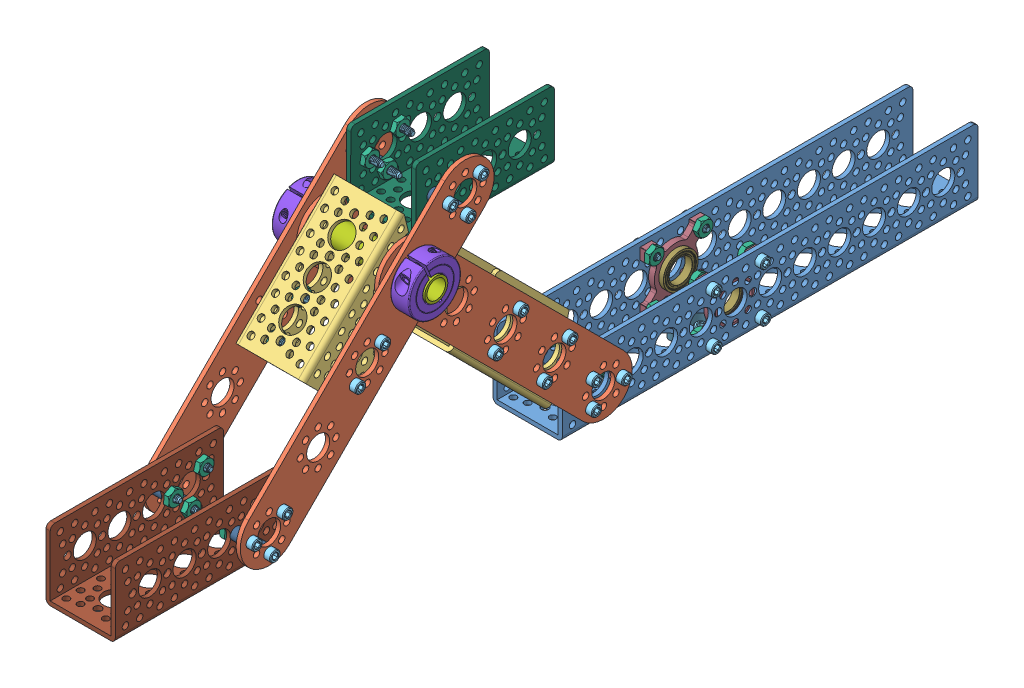
SolidWorks assembly Rocker-Bogie Assembly, configuration Default. Lengths in mm.
Overall size (76.23 183.41 474.44).
136 component instances, 15 part files, 93 mates.
Components (placement in the parent):
- 9 Aluminum Channel-1: 9 Aluminum Channel [Default] at (59.7969 112.1361 56.5133) size (38.1 38.1 228.6)
- Pattern F Bracket-1: Pattern F Bracket [Default] at (58.5269 185.0676 319.9448) x (0 0.707107 0.707107) z (0 -0.707107 0.707107) size (184.15 2.29 31.75)
- 3 Aluminum Channel Mod-1: 3 Aluminum Channel Mod [Default] at (59.7969 131.1861 293.004) x (1 0 0) z (0 0.707107 0.707107) size (38.1 38.1 76.2)
- 6-32 Washer-3: 6-32 Washer [Default] at (58.5269 124.2713 272.9781) x (0 0 -1) z (1 0 0) size (6.35 6.35 1.27)
- 6-32 Washer-6: 6-32 Washer [Default] at (58.5269 178.1528 326.8596) x (0 0 -1) z (1 0 0) size (6.35 6.35 1.27)
- 6-32 Washer-7: 6-32 Washer [Default] at (58.5269 191.9824 313.03) x (0 0 -1) z (1 0 0) size (6.35 6.35 1.27)
- 6-32 Washer-8: 6-32 Washer [Default] at (58.5269 165.0416 286.0892) x (0 -0.924225 -0.381849) z (1 0 0) size (6.35 6.35 1.27)
- 6-32 Washer-9: 6-32 Washer [Default] at (58.5269 151.212 299.9188) x (0 0 -1) z (1 0 0) size (6.35 6.35 1.27)
- 6-32_SHCS-2: 6-32_SHCS [6-32 SHCS X .375] at (65.7659 178.1528 326.8596) x (0 0.924225 0.381849) z (-1 0 0) size (5.74 5.74 13.03)
- 6-32_SHCS-6: 6-32_SHCS [6-32 SHCS X .375] at (65.7659 191.9824 313.03) x (0 0.924225 0.381849) z (-1 0 0) size (5.74 5.74 13.03)
- 6-32_SHCS-7: 6-32_SHCS [6-32 SHCS X .375] at (65.7659 165.0416 286.0892) x (0 0.924225 0.381849) z (-1 0 0) size (5.74 5.74 13.03)
- 6-32_SHCS-8: 6-32_SHCS [6-32 SHCS X .375] at (65.7659 124.2713 272.9781) x (0 0.924225 0.381849) z (-1 0 0) size (5.74 5.74 13.03)
- 6-32_SHCS-9: 6-32_SHCS [6-32 SHCS X .375] at (65.7659 151.212 299.9188) x (0 0 1) z (-1 0 0) size (5.74 5.74 13.03)
- hex_nut-1: hex_nut [#6-32] at (62.0829 191.9824 313.03) x (0 0.381849 -0.924225) z (0 -0.924225 -0.381849) size (7.92 2.9 10.06)
- hex_nut-2: hex_nut [#6-32] at (62.0829 151.212 299.9188) x (0 0.381849 -0.924225) z (0 -0.924225 -0.381849) size (7.92 2.9 10.06)
- hex_nut-3: hex_nut [#6-32] at (62.0829 124.2713 272.9781) x (0 0.381849 -0.924225) z (0 -0.924225 -0.381849) size (7.92 2.9 10.06)
- hex_nut-4: hex_nut [#6-32] at (62.0829 165.0416 286.0892) x (0 -0.870942 -0.491386) z (0 -0.491386 0.870942) size (7.92 2.9 10.06)
- hex_nut-5: hex_nut [#6-32] at (62.0829 178.1528 326.8596) x (0 0.381849 -0.924225) z (0 -0.924225 -0.381849) size (7.92 2.9 10.06)
- hex_nut-10: hex_nut [#6-32] at (62.0829 131.0154 256.2858) x (0 0.399577 0.9167) z (0 0.9167 -0.399577) size (7.92 2.9 10.06)
- hex_nut-11: hex_nut [#6-32] at (62.0829 138.338 272.7325) x (0 -0.936988 -0.349362) z (0 -0.349362 0.936988) size (7.92 2.9 10.06)
- 6-32 Washer-10: 6-32 Washer [Default] at (58.5269 131.0154 256.2858) x (0 0.71934 0.694658) z (1 0 0) size (6.35 6.35 1.27)
- 6-32 Washer-11: 6-32 Washer [Default] at (58.5269 138.338 272.7325) x (0 -0.999391 0.034899) z (1 0 0) size (6.35 6.35 1.27)
- 6-32_SHCS-10: 6-32_SHCS [6-32 SHCS X .375] at (65.7659 131.0154 256.2858) x (0 -0.9167 0.399577) z (-1 0 0) size (5.74 5.74 13.03)
- 6-32_SHCS-11: 6-32_SHCS [6-32 SHCS X .375] at (65.7659 138.338 272.7325) x (0 0.349362 -0.936988) z (-1 0 0) size (5.74 5.74 13.03)
- 3inch Aluminum Rod-1: 3inch Aluminum Rod [Default] at (41.0962 238.9491 373.8263) x (1 0 0) z (0 0.999969 -0.00781) size (76.2 12.7 12.7)
- .5in Collared Clamp-1: .5in Collared Clamp [6157K14] at (46.2556 238.9491 373.8263) x (0 -0.38629 0.922377) z (-1 0 0) size (28.57 28.59 10.38)
- 0.5 Nylon Plastic Washer-1: 0.5 Nylon Plastic Washer [Default] at (53.7009 238.9491 373.8263) x (0 0 -1) z (1 0 0) size (19.05 19.05 1.27)
- 0.5 Nylon Plastic Washer-2: 0.5 Nylon Plastic Washer [Default] at (59.7969 238.9491 373.8263) x (0 0 1) z (-1 0 0) size (19.05 19.05 1.27)
- 0.5 Nylon Plastic Washer-3: 0.5 Nylon Plastic Washer [Default] at (56.2409 238.9491 373.8263) x (0 0 1) z (-1 0 0) size (19.05 19.05 1.27)
- Pattern F Bracket-2: Pattern F Bracket [Default] at (51.4149 212.0374 400.7961) x (0 -0.706344 0.707869) z (0 0.707869 0.706344) size (184.15 2.29 31.75)
- 3 Aluminum Channel Mod-2: 3 Aluminum Channel Mod [Default] at (97.8969 265.8899 373.7973) x (-1 0 0) z (0 -0.706344 0.707869) size (38.1 38.1 76.2)
- 6-32_L0_25 Spacer-1: 6-32_L0_25 Spacer [Default] at (53.7009 205.1301 407.7184) size (6.35 6.35 6.35)
- 6-32_L0_25 Spacer-2: 6-32_L0_25 Spacer [Default] at (53.7009 256.0818 346.8671) size (6.35 6.35 6.35)
- 6-32_L0_25 Spacer-4: 6-32_L0_25 Spacer [Default] at (53.7009 148.435 454.7463) size (6.35 6.35 6.35)
- 6-32_L0_25 Spacer-5: 6-32_L0_25 Spacer [Default] at (53.7009 218.9448 393.8739) size (6.35 6.35 6.35)
- 6-32_SHCS-12: 6-32_SHCS [6-32 SHCS X .750] at (70.4649 205.1301 407.7184) x (0 0.924225 0.381849) z (-1 0 0) size (5.74 5.74 22.56)
- 6-32_SHCS-13: 6-32_SHCS [6-32 SHCS X .750] at (70.4649 256.0818 346.8671) x (0 0.924225 0.381849) z (-1 0 0) size (5.74 5.74 22.56)
- 6-32_SHCS-15: 6-32_SHCS [6-32 SHCS X .750] at (70.4649 218.9448 393.8739) x (0 0.924225 0.381849) z (-1 0 0) size (5.74 5.74 22.56)
- 6-32_SHCS-16: 6-32_SHCS [6-32 SHCS X .625] at (67.2899 148.435 454.7463) x (0 0.616938 0.787012) z (-1 0 0) size (5.74 5.74 19.38)
- 3.75 Aluminum Channel-1: 3.75 Aluminum Channel [Default] at (59.7969 139.1435 435.7063) x (1 0 0) z (0 0.001078 0.999999) size (38.1 38.1 95.25)
- hex_nut-12: hex_nut [#6-32] at (62.0829 256.0818 346.8671) x (0 0.381849 -0.924225) z (0 -0.924225 -0.381849) size (7.92 2.9 10.06)
- hex_nut-14: hex_nut [#6-32] at (62.0829 218.9448 393.8739) x (0 0.381849 -0.924225) z (0 -0.924225 -0.381849) size (7.92 2.9 10.06)
- hex_nut-15: hex_nut [#6-32] at (62.0829 205.1301 407.7184) x (0 0.381849 -0.924225) z (0 -0.924225 -0.381849) size (7.92 2.9 10.06)
- hex_nut-16: hex_nut [#6-32] at (62.0829 148.435 454.7463) x (0 -1 0) z (0 0 1) size (7.92 2.9 10.06)
- hex_nut-17: hex_nut [#6-32] at (62.0829 272.6463 339.8148) x (0 0.399577 0.9167) z (0 0.9167 -0.399577) size (7.92 2.9 10.06)
- hex_nut-18: hex_nut [#6-32] at (62.0829 266.2127 356.6292) x (0 -0.936988 -0.349362) z (0 -0.349362 0.936988) size (7.92 2.9 10.06)
- 6-32_L0_25 Spacer-6: 6-32_L0_25 Spacer [Default] at (53.7009 272.6463 339.8148) x (1 0 0) z (0 -0.71934 -0.694658) size (6.35 6.35 6.35)
- 6-32_L0_25 Spacer-7: 6-32_L0_25 Spacer [Default] at (53.7009 266.2127 356.6292) x (1 0 0) z (0 0.999391 -0.034899) size (6.35 6.35 6.35)
- 6-32_SHCS-17: 6-32_SHCS [6-32 SHCS X .750] at (70.4649 272.6463 339.8148) x (0 -0.9167 0.399577) z (-1 0 0) size (5.74 5.74 22.56)
- 6-32_SHCS-18: 6-32_SHCS [6-32 SHCS X .750] at (70.4649 266.2127 356.6292) x (0 0.349362 -0.936988) z (-1 0 0) size (5.74 5.74 22.56)
- hex_nut-19: hex_nut [#6-32] at (62.0829 164.9995 447.694) x (0 0.694658 -0.71934) z (0 -0.71934 -0.694658) size (7.92 2.9 10.06)
- hex_nut-20: hex_nut [#6-32] at (62.0829 158.5658 464.5084) x (0 0.034899 0.999391) z (0 0.999391 -0.034899) size (7.92 2.9 10.06)
- 6-32_L0_25 Spacer-8: 6-32_L0_25 Spacer [Default] at (53.7009 164.9995 447.694) x (1 0 0) z (0 -0.71934 -0.694658) size (6.35 6.35 6.35)
- 6-32_L0_25 Spacer-9: 6-32_L0_25 Spacer [Default] at (53.7009 158.5658 464.5084) x (1 0 0) z (0 0.999391 -0.034899) size (6.35 6.35 6.35)
- 6-32_SHCS-19: 6-32_SHCS [6-32 SHCS X .625] at (67.2899 164.9995 447.694) x (0 -0.99469 -0.102916) z (-1 0 0) size (5.74 5.74 19.38)
- 6-32_SHCS-20: 6-32_SHCS [6-32 SHCS X .625] at (67.2899 158.5658 464.5084) x (0 0.765001 -0.644029) z (-1 0 0) size (5.74 5.74 19.38)
- 6-32_L0_25 Spacer-10: 6-32_L0_25 Spacer [Default] at (103.9929 158.5658 464.5084) x (-1 0 0) z (0 -0.999391 0.034899) size (6.35 6.35 6.35)
- 6-32_SHCS-21: 6-32_SHCS [6-32 SHCS X .625] at (90.4039 158.5658 464.5084) x (0 -0.765001 0.644029) z (1 0 0) size (5.74 5.74 19.38)
- 6-32_SHCS-22: 6-32_SHCS [6-32 SHCS X .625] at (90.4039 148.435 454.7463) x (0 -0.616938 -0.787012) z (1 0 0) size (5.74 5.74 19.38)
- 6-32_L0_25 Spacer-11: 6-32_L0_25 Spacer [Default] at (103.9929 148.435 454.7463) x (-1 0 0) z (0 0 -1) size (6.35 6.35 6.35)
- 6-32_L0_25 Spacer-12: 6-32_L0_25 Spacer [Default] at (103.9929 164.9995 447.694) x (-1 0 0) z (0 0.71934 0.694658) size (6.35 6.35 6.35)
- 6-32_SHCS-23: 6-32_SHCS [6-32 SHCS X .625] at (90.4039 164.9995 447.694) x (0 0.99469 0.102916) z (1 0 0) size (5.74 5.74 19.38)
- Pattern F Bracket-3: Pattern F Bracket [Default] at (106.2789 212.0374 400.7961) x (0 0.706344 -0.707869) z (0 0.707869 0.706344) size (184.15 2.29 31.75)
- hex_nut-21: hex_nut [#6-32] at (95.6109 148.435 454.7463) x (0 -1 0) z (0 0 -1) size (7.92 2.9 10.06)
- hex_nut-22: hex_nut [#6-32] at (95.6109 158.5658 464.5084) x (0 0.034899 0.999391) z (0 -0.999391 0.034899) size (7.92 2.9 10.06)
- hex_nut-23: hex_nut [#6-32] at (95.6109 164.9995 447.694) x (0 0.694658 -0.71934) z (0 0.71934 0.694658) size (7.92 2.9 10.06)
- hex_nut-24: hex_nut [#6-32] at (95.6109 205.1301 407.7184) x (0 0.381849 -0.924225) z (0 0.924225 0.381849) size (7.92 2.9 10.06)
- 6-32_SHCS-24: 6-32_SHCS [6-32 SHCS X .750] at (87.2289 205.1301 407.7184) x (0 -0.924225 -0.381849) z (1 0 0) size (5.74 5.74 22.56)
- 6-32_SHCS-25: 6-32_SHCS [6-32 SHCS X .750] at (87.2289 218.9448 393.8739) x (0 -0.924225 -0.381849) z (1 0 0) size (5.74 5.74 22.56)
- hex_nut-25: hex_nut [#6-32] at (95.6109 218.9448 393.8739) x (0 0.381849 -0.924225) z (0 0.924225 0.381849) size (7.92 2.9 10.06)
- .5in Collared Clamp-2: .5in Collared Clamp [6157K14] at (111.4383 238.9491 373.8263) x (0 0.38629 -0.922377) z (1 0 0) size (28.57 28.59 10.38)
- 0.5 Nylon Plastic Washer-4: 0.5 Nylon Plastic Washer [Default] at (102.7229 238.9491 373.8263) x (0 0 -1) z (1 0 0) size (19.05 19.05 1.27)
- 0.5 Nylon Plastic Washer-5: 0.5 Nylon Plastic Washer [Default] at (102.7229 238.9491 373.8263) x (0 0 1) z (-1 0 0) size (19.05 19.05 1.27)
- 0.5 Nylon Plastic Washer-6: 0.5 Nylon Plastic Washer [Default] at (99.1669 238.9491 373.8263) x (0 0 1) z (-1 0 0) size (19.05 19.05 1.27)
- 6-32_L0_25 Spacer-13: 6-32_L0_25 Spacer [Default] at (103.9929 205.1301 407.7184) x (-1 0 0) z (0 0 -1) size (6.35 6.35 6.35)
- 6-32_L0_25 Spacer-14: 6-32_L0_25 Spacer [Default] at (103.9929 218.9448 393.8739) x (-1 0 0) z (0 0 -1) size (6.35 6.35 6.35)
- 6-32_L0_25 Spacer-15: 6-32_L0_25 Spacer [Default] at (103.9929 266.2127 356.6292) x (-1 0 0) z (0 -0.999391 0.034899) size (6.35 6.35 6.35)
- 6-32_L0_25 Spacer-16: 6-32_L0_25 Spacer [Default] at (103.9929 272.6463 339.8148) x (-1 0 0) z (0 0.71934 0.694658) size (6.35 6.35 6.35)
- 6-32_L0_25 Spacer-17: 6-32_L0_25 Spacer [Default] at (103.9929 256.0818 346.8671) x (-1 0 0) z (0 0 -1) size (6.35 6.35 6.35)
- 6-32_SHCS-26: 6-32_SHCS [6-32 SHCS X .750] at (87.2289 256.0818 346.8671) x (0 -0.924225 -0.381849) z (1 0 0) size (5.74 5.74 22.56)
- 6-32_SHCS-27: 6-32_SHCS [6-32 SHCS X .750] at (87.2289 266.2127 356.6292) x (0 -0.349362 0.936988) z (1 0 0) size (5.74 5.74 22.56)
- 6-32_SHCS-28: 6-32_SHCS [6-32 SHCS X .750] at (87.2289 272.6463 339.8148) x (0 0.9167 -0.399577) z (1 0 0) size (5.74 5.74 22.56)
- 6-32_SHCS-29: 6-32_SHCS [6-32 SHCS X .375] at (91.9279 191.9824 313.03) x (0 -0.924225 -0.381849) z (1 0 0) size (5.74 5.74 13.03)
- 6-32_SHCS-30: 6-32_SHCS [6-32 SHCS X .375] at (91.9279 165.0416 286.0892) x (0 -0.924225 -0.381849) z (1 0 0) size (5.74 5.74 13.03)
- 6-32_SHCS-31: 6-32_SHCS [6-32 SHCS X .375] at (91.9279 131.0154 256.2858) x (0 0.9167 -0.399577) z (1 0 0) size (5.74 5.74 13.03)
- 6-32_SHCS-32: 6-32_SHCS [6-32 SHCS X .375] at (91.9279 138.338 272.7325) x (0 -0.349362 0.936988) z (1 0 0) size (5.74 5.74 13.03)
- 6-32_SHCS-33: 6-32_SHCS [6-32 SHCS X .375] at (91.9279 151.212 299.9188) x (0 0 -1) z (1 0 0) size (5.74 5.74 13.03)
- 6-32_SHCS-34: 6-32_SHCS [6-32 SHCS X .375] at (91.9279 178.1528 326.8596) x (0 -0.924225 -0.381849) z (1 0 0) size (5.74 5.74 13.03)
- 6-32_SHCS-35: 6-32_SHCS [6-32 SHCS X .375] at (91.9279 124.2713 272.9781) x (0 -0.924225 -0.381849) z (1 0 0) size (5.74 5.74 13.03)
- 6-32 Washer-12: 6-32 Washer [Default] at (97.8969 131.0154 256.2858) x (0 0.71934 0.694658) z (1 0 0) size (6.35 6.35 1.27)
- 6-32 Washer-13: 6-32 Washer [Default] at (97.8969 124.2713 272.9781) x (0 0 -1) z (1 0 0) size (6.35 6.35 1.27)
- 6-32 Washer-14: 6-32 Washer [Default] at (97.8969 138.338 272.7325) x (0 -0.999391 0.034899) z (1 0 0) size (6.35 6.35 1.27)
- 6-32 Washer-15: 6-32 Washer [Default] at (97.8969 151.212 299.9188) x (0 0 -1) z (1 0 0) size (6.35 6.35 1.27)
- 6-32 Washer-16: 6-32 Washer [Default] at (97.8969 165.0416 286.0892) x (0 -0.924225 -0.381849) z (1 0 0) size (6.35 6.35 1.27)
- 6-32 Washer-17: 6-32 Washer [Default] at (97.8969 191.9824 313.03) x (0 0 -1) z (1 0 0) size (6.35 6.35 1.27)
- 6-32 Washer-18: 6-32 Washer [Default] at (97.8969 178.1528 326.8596) x (0 0 -1) z (1 0 0) size (6.35 6.35 1.27)
- Pattern F Bracket-4: Pattern F Bracket [Default] at (101.4529 185.0676 319.9448) x (0 -0.707107 -0.707107) z (0 0.707107 -0.707107) size (184.15 2.29 31.75)
- 0.5 Pillow Bearing Block-1: 0.5 Pillow Bearing Block [Default] at (54.9779 139.4622 174.7264) x (0 -0.904025 -0.427479) z (0 -0.427479 0.904025) size (44.3 7.64 44.3)
  - 0.5 Bearing-1: 0.5 Bearing [Default] at (1.0111 10.8528 17.222) size (19.05 3.97 19.05)
  - 0.5 Bearing Block-1: 0.5 Bearing Block [Default] at (1.0111 10.28 17.222) x (-0.904025 0 -0.427479) z (-0.427479 0 0.904025) size (33.27 5.08 33.27)
- 0.5 Pillow Bearing Block-2: 0.5 Pillow Bearing Block [Default] at (102.716 116.0492 198.1394) x (0 -0.427479 -0.904025) z (0 0.904025 -0.427479) size (44.3 7.64 44.3)
  - 0.5 Bearing-1: 0.5 Bearing [Default] at (1.0111 10.8528 17.222) size (19.05 3.97 19.05)
  - 0.5 Bearing Block-1: 0.5 Bearing Block [Default] at (1.0111 10.28 17.222) x (-0.904025 0 -0.427479) z (-0.427479 0 0.904025) size (33.27 5.08 33.27)
- 6-32_SHCS-36: 6-32_SHCS [6-32 SHCS X .375] at (69.3219 144.6564 176.3929) x (0 0.00007 1) z (-1 0 0) size (5.74 5.74 13.03)
- hex_nut-26: hex_nut [#6-32] at (65.2579 144.6564 176.3929) x (0 0.442098 -0.896967) z (0 -0.896967 -0.442098) size (7.92 2.9 10.06)
- 6-32_SHCS-37: 6-32_SHCS [6-32 SHCS X .375] at (69.3219 117.7157 176.3929) x (0 1 -0.00007) z (-1 0 0) size (5.74 5.74 13.03)
- 6-32_SHCS-38: 6-32_SHCS [6-32 SHCS X .375] at (69.3219 117.7157 203.3337) x (0 -0.00007 -1) z (-1 0 0) size (5.74 5.74 13.03)
- 6-32_SHCS-39: 6-32_SHCS [6-32 SHCS X .375] at (69.3219 144.6564 203.3337) x (0 -1 0.00007) z (-1 0 0) size (5.74 5.74 13.03)
- hex_nut-27: hex_nut [#6-32] at (65.2579 117.7157 176.3929) x (0 -0.896967 -0.442098) z (0 -0.442098 0.896967) size (7.92 2.9 10.06)
- hex_nut-28: hex_nut [#6-32] at (65.2579 117.7157 203.3337) x (0 -0.442098 0.896967) z (0 0.896967 0.442098) size (7.92 2.9 10.06)
- hex_nut-29: hex_nut [#6-32] at (65.2579 144.6564 203.3337) x (0 0.896967 0.442098) z (0 0.442098 -0.896967) size (7.92 2.9 10.06)
- 6-32_SHCS-40: 6-32_SHCS [6-32 SHCS X .375] at (88.3719 144.6564 176.3929) x (0 -0.00007 -1) z (1 0 0) size (5.74 5.74 13.03)
- hex_nut-30: hex_nut [#6-32] at (92.4359 144.6564 176.3929) x (0 0.442098 -0.896967) z (0 0.896967 0.442098) size (7.92 2.9 10.06)
- 6-32_SHCS-41: 6-32_SHCS [6-32 SHCS X .375] at (88.3719 117.7157 176.3929) x (0 -1 0.00007) z (1 0 0) size (5.74 5.74 13.03)
- 6-32_SHCS-42: 6-32_SHCS [6-32 SHCS X .375] at (88.3719 117.7157 203.3337) x (0 0.00007 1) z (1 0 0) size (5.74 5.74 13.03)
- 6-32_SHCS-43: 6-32_SHCS [6-32 SHCS X .375] at (88.3719 144.6564 203.3337) x (0 1 -0.00007) z (1 0 0) size (5.74 5.74 13.03)
- hex_nut-31: hex_nut [#6-32] at (92.4359 117.7157 176.3929) x (0 -0.896967 -0.442098) z (0 0.442098 -0.896967) size (7.92 2.9 10.06)
- hex_nut-32: hex_nut [#6-32] at (92.4359 117.7157 203.3337) x (0 -0.442098 0.896967) z (0 -0.896967 -0.442098) size (7.92 2.9 10.06)
- hex_nut-33: hex_nut [#6-32] at (92.4359 144.6564 203.3337) x (0 0.896967 0.442098) z (0 -0.442098 0.896967) size (7.92 2.9 10.06)
- 0.5 Bore Side Tapped Clamping Hub-1: 0.5 Bore Side Tapped Clamping Hub [Default] at (112.3725 93.4655 176.8061) size (20.57 7.21 26.29)
  - 545600-1: 545600 [Default] at (-33.5255 9.1455 13.0572) size (20.57 7.21 26.29)
- 6-32_SHCS-44: 6-32_SHCS [6-32 SHCS X .375] at (71.9322 104.8971 196.7781) x (1 0 0) z (0 1 0) size (5.74 5.74 13.03)
- 6-32_SHCS-45: 6-32_SHCS [6-32 SHCS X .375] at (71.9322 104.8971 182.9485) x (0 0 1) z (0 1 0) size (5.74 5.74 13.03)
- 6-32_SHCS-46: 6-32_SHCS [6-32 SHCS X .375] at (85.7617 104.8971 182.9485) x (-1 0 0) z (0 1 0) size (5.74 5.74 13.03)
- 6-32_SHCS-47: 6-32_SHCS [6-32 SHCS X .375] at (85.7617 104.8971 196.7781) x (0 0 -1) z (0 1 0) size (5.74 5.74 13.03)
- hex_nut-34: hex_nut [#6-32] at (95.6109 165.0416 286.0892) x (0 -0.870942 -0.491386) z (0 0.491386 -0.870942) size (7.92 2.9 10.06)
- hex_nut-35: hex_nut [#6-32] at (95.6109 151.212 299.9188) x (0 0.381849 -0.924225) z (0 0.924225 0.381849) size (7.92 2.9 10.06)
- hex_nut-36: hex_nut [#6-32] at (95.6109 138.338 272.7325) x (0 -0.936988 -0.349362) z (0 0.349362 -0.936988) size (7.92 2.9 10.06)
- hex_nut-37: hex_nut [#6-32] at (95.6109 124.2713 272.9781) x (0 0.381849 -0.924225) z (0 0.924225 0.381849) size (7.92 2.9 10.06)
- hex_nut-38: hex_nut [#6-32] at (95.6109 131.0154 256.2858) x (0 0.399577 0.9167) z (0 -0.9167 0.399577) size (7.92 2.9 10.06)
- hex_nut-39: hex_nut [#6-32] at (95.6109 191.9824 313.03) x (0 0.381849 -0.924225) z (0 0.924225 0.381849) size (7.92 2.9 10.06)
- hex_nut-40: hex_nut [#6-32] at (95.6109 178.1528 326.8596) x (0 0.381849 -0.924225) z (0 0.924225 0.381849) size (7.92 2.9 10.06)
- hex_nut-41: hex_nut [#6-32] at (95.6109 266.2127 356.6292) x (0 -0.936988 -0.349362) z (0 0.349362 -0.936988) size (7.92 2.9 10.06)
- hex_nut-42: hex_nut [#6-32] at (95.6109 272.6463 339.8148) x (0 0.399577 0.9167) z (0 -0.9167 0.399577) size (7.92 2.9 10.06)
- hex_nut-43: hex_nut [#6-32] at (95.6109 256.0818 346.8671) x (0 0.381849 -0.924225) z (0 0.924225 0.381849) size (7.92 2.9 10.06)
- 3 Aluminum Channel-2: 3 Aluminum Channel [Default] at (60.0509 246.7492 289.7271) x (1 0 0) z (0 0.001078 0.999999) size (38.1 38.1 76.2)
Mates (geometry in assembly coordinates):
- Concentric1: concentric aligned: cylinder of 9 Aluminum Channel-1 through (97.8969 124.2713 272.9781) axis (1 0 0) radius 1.778; cylinder of 6-32_SHCS-8 through (43.5409 124.2713 272.9781) axis (1 0 0) radius 2.8702
- Concentric2: concentric anti-aligned: cylinder of 9 Aluminum Channel-1 through (97.8969 124.2713 272.9781) axis (1 0 0) radius 1.778; cylinder of 6-32 Washer-3 through (59.7969 124.2713 272.9781) axis (-1 0 0) radius 3.175
- Concentric3: concentric aligned: cylinder of 9 Aluminum Channel-1 through (97.8969 124.2713 272.9781) axis (1 0 0) radius 1.778; cylinder of hex_nut-3 through (62.159 124.2713 272.9781) axis (1 0 0) radius 1.323
- Concentric4: concentric aligned: cylinder of 3 Aluminum Channel Mod-1 through (97.8969 151.212 299.9188) axis (1 0 0) radius 1.778; cylinder of 6-32_SHCS-9 through (43.5409 151.212 299.9188) axis (1 0 0) radius 2.8702
- Concentric5: concentric anti-aligned: cylinder of 3 Aluminum Channel Mod-1 through (97.8969 151.212 299.9188) axis (1 0 0) radius 1.778; cylinder of 6-32 Washer-9 through (59.7969 151.212 299.9188) axis (-1 0 0) radius 3.175
- Concentric6: concentric aligned: cylinder of 3 Aluminum Channel Mod-1 through (97.8969 151.212 299.9188) axis (1 0 0) radius 1.778; cylinder of hex_nut-2 through (62.159 151.212 299.9188) axis (1 0 0) radius 1.323
- Concentric7: concentric aligned: cylinder of 3 Aluminum Channel Mod-1 through (97.8969 165.0416 286.0892) axis (1 0 0) radius 1.778; cylinder of 6-32_SHCS-7 through (43.5409 165.0416 286.0892) axis (1 0 0) radius 2.8702
- Concentric8: concentric anti-aligned: circle of hex_nut-4; cylinder of 6-32 Washer-8 through (59.7969 165.0416 286.0892) axis (-1 0 0) radius 3.175
- Concentric9: concentric aligned: circle of hex_nut-4; cylinder of 3 Aluminum Channel Mod-1 through (97.8969 165.0416 286.0892) axis (1 0 0) radius 1.778
- Concentric10: concentric anti-aligned: cylinder of 3 Aluminum Channel Mod-1 through (97.8969 191.9824 313.03) axis (1 0 0) radius 1.778; cylinder of 6-32 Washer-7 through (59.7969 191.9824 313.03) axis (-1 0 0) radius 3.175
- Concentric11: concentric aligned: cylinder of 3 Aluminum Channel Mod-1 through (97.8969 191.9824 313.03) axis (1 0 0) radius 1.778; cylinder of 6-32_SHCS-6 through (43.5409 191.9824 313.03) axis (1 0 0) radius 2.8702
- Concentric12: concentric aligned: cylinder of 3 Aluminum Channel Mod-1 through (97.8969 191.9824 313.03) axis (1 0 0) radius 1.778; cylinder of hex_nut-1 through (62.159 191.9824 313.03) axis (1 0 0) radius 1.323
- Concentric13: concentric anti-aligned: cylinder of 3 Aluminum Channel Mod-1 through (97.8969 178.1528 326.8596) axis (1 0 0) radius 1.778; cylinder of 6-32 Washer-6 through (59.7969 178.1528 326.8596) axis (-1 0 0) radius 3.175
- Concentric14: concentric aligned: cylinder of 3 Aluminum Channel Mod-1 through (97.8969 178.1528 326.8596) axis (1 0 0) radius 1.778; cylinder of 6-32_SHCS-2 through (43.5409 178.1528 326.8596) axis (1 0 0) radius 2.8702
- Concentric15: concentric aligned: cylinder of 3 Aluminum Channel Mod-1 through (97.8969 178.1528 326.8596) axis (1 0 0) radius 1.778; cylinder of hex_nut-5 through (62.159 178.1528 326.8596) axis (1 0 0) radius 1.323
- Coincident1: coincident aligned: plane of 9 Aluminum Channel-1 through (59.7969 112.1361 285.1133) normal (-1 0 0); plane of 3 Aluminum Channel Mod-1 through (59.7969 185.0676 346.8856) normal (-1 0 0)
- Coincident2: coincident anti-aligned: plane of 9 Aluminum Channel-1 through (59.7969 112.1361 285.1133) normal (-1 0 0); plane of 6-32 Washer-3 through (59.7969 124.2713 272.9781) normal (1 0 0)
- Coincident3: coincident anti-aligned: plane of 9 Aluminum Channel-1 through (59.7969 112.1361 285.1133) normal (-1 0 0); plane of 6-32 Washer-9 through (59.7969 151.212 299.9188) normal (1 0 0)
- Coincident5: coincident anti-aligned: plane of 9 Aluminum Channel-1 through (59.7969 112.1361 285.1133) normal (-1 0 0); plane of 6-32 Washer-7 through (59.7969 191.9824 313.03) normal (1 0 0)
- Coincident6: coincident anti-aligned: plane of 9 Aluminum Channel-1 through (59.7969 112.1361 285.1133) normal (-1 0 0); plane of 6-32 Washer-6 through (59.7969 178.1528 326.8596) normal (1 0 0)
- Coincident7: coincident anti-aligned: plane of 9 Aluminum Channel-1 through (59.7969 112.1361 285.1133) normal (-1 0 0); plane of 6-32 Washer-8 through (59.7969 165.0416 286.0892) normal (1 0 0)
- Coincident8: coincident anti-aligned: plane of Pattern F Bracket-1 through (58.5269 131.1861 266.0633) normal (1 0 0); plane of 6-32 Washer-3 through (58.5269 124.2713 272.9781) normal (-1 0 0)
- Concentric16: concentric anti-aligned: cylinder of 9 Aluminum Channel-1 through (97.8969 131.1861 266.0633) axis (1 0 0) radius 6.3627; cylinder of Pattern F Bracket-1 through (56.2409 131.1861 266.0633) axis (-1 0 0) radius 6.3627
- Concentric17: concentric anti-aligned: cylinder of 9 Aluminum Channel-1 through (97.8969 124.2713 272.9781) axis (1 0 0) radius 1.778; cylinder of Pattern F Bracket-1 through (56.2409 124.2713 272.9781) axis (-1 0 0) radius 1.778
- Coincident9: coincident anti-aligned: plane of Pattern F Bracket-1 through (56.2409 131.1861 266.0633) normal (-1 0 0); plane of 6-32_SHCS-8 through (56.2409 124.2713 272.9781) normal (1 0 0)
- Coincident10: coincident anti-aligned: plane of Pattern F Bracket-1 through (56.2409 131.1861 266.0633) normal (-1 0 0); plane of 6-32_SHCS-7 through (56.2409 165.0416 286.0892) normal (1 0 0)
- Coincident11: coincident anti-aligned: plane of Pattern F Bracket-1 through (56.2409 131.1861 266.0633) normal (-1 0 0); plane of 6-32_SHCS-9 through (56.2409 151.212 299.9188) normal (1 0 0)
- Coincident12: coincident anti-aligned: plane of Pattern F Bracket-1 through (56.2409 131.1861 266.0633) normal (-1 0 0); plane of 6-32_SHCS-6 through (56.2409 191.9824 313.03) normal (1 0 0)
- Coincident13: coincident anti-aligned: plane of Pattern F Bracket-1 through (56.2409 131.1861 266.0633) normal (-1 0 0); plane of 6-32_SHCS-2 through (56.2409 178.1528 326.8596) normal (1 0 0)
- Concentric18: concentric anti-aligned: cylinder of Pattern F Bracket-1 through (56.2409 158.1268 293.004) axis (-1 0 0) radius 6.3627; cylinder of 3 Aluminum Channel Mod-1 through (97.8969 158.1268 293.004) axis (1 0 0) radius 6.3627
- Concentric19: concentric anti-aligned: cylinder of Pattern F Bracket-1 through (56.2409 185.0676 319.9448) axis (-1 0 0) radius 6.3627; cylinder of 3 Aluminum Channel Mod-1 through (97.8969 185.0676 319.9448) axis (1 0 0) radius 6.3627
- Coincident14: coincident anti-aligned: plane of 9 Aluminum Channel-1 through (62.0829 150.2361 285.1133) normal (1 0 0); plane of hex_nut-3 through (62.0829 129.1012 279.2609) normal (-1 0 0)
- Coincident15: coincident anti-aligned: plane of 9 Aluminum Channel-1 through (62.0829 150.2361 285.1133) normal (1 0 0); plane of hex_nut-2 through (62.0829 156.042 306.2016) normal (-1 0 0)
- Coincident16: coincident anti-aligned: plane of 9 Aluminum Channel-1 through (62.0829 150.2361 285.1133) normal (1 0 0); plane of hex_nut-4 through (62.0829 171.8651 282.059) normal (-1 0 0)
- Coincident17: coincident anti-aligned: plane of 9 Aluminum Channel-1 through (62.0829 150.2361 285.1133) normal (1 0 0); plane of hex_nut-5 through (62.0829 182.9828 333.1424) normal (-1 0 0)
- Coincident18: coincident anti-aligned: plane of 9 Aluminum Channel-1 through (62.0829 150.2361 285.1133) normal (1 0 0); plane of hex_nut-1 through (62.0829 196.8124 319.3128) normal (-1 0 0)
- Concentric20: concentric anti-aligned: cylinder of Pattern F Bracket-1 through (56.2409 238.9491 373.8263) axis (-1 0 0) radius 6.3627; circle of 0.5 Nylon Plastic Washer-1
- Concentric21: concentric anti-aligned: cylinder of Pattern F Bracket-1 through (56.2409 238.9491 373.8263) axis (-1 0 0) radius 6.3627; cylinder of 0.5 Nylon Plastic Washer-3 through (54.9709 238.9491 373.8263) axis (1 0 0) radius 6.35
- Concentric22: concentric anti-aligned: cylinder of Pattern F Bracket-1 through (56.2409 238.9491 373.8263) axis (-1 0 0) radius 6.3627; cylinder of 0.5 Nylon Plastic Washer-2 through (58.5269 238.9491 373.8263) axis (1 0 0) radius 6.35
- Concentric23: concentric aligned: cylinder of Pattern F Bracket-1 through (56.2409 238.9491 373.8263) axis (-1 0 0) radius 6.3627; cylinder of 3inch Aluminum Rod-1 through (117.2962 238.9491 373.8263) axis (-1 0 0) radius 6.35
- Concentric24: concentric anti-aligned: cylinder of Pattern F Bracket-1 through (56.2409 238.9491 373.8263) axis (-1 0 0) radius 6.3627; cylinder of .5in Collared Clamp-1 through (41.0962 238.9491 373.8263) axis (1 0 0) radius 6.35
- Concentric25: concentric anti-aligned: cylinder of Pattern F Bracket-1 through (56.2409 238.9491 373.8263) axis (-1 0 0) radius 6.3627; cylinder of Pattern F Bracket-2 through (53.7009 238.9491 373.8263) axis (1 0 0) radius 6.3627
- Concentric26: concentric aligned: cylinder of 3inch Aluminum Rod-1 through (117.2962 238.9491 373.8263) axis (-1 0 0) radius 6.35; cylinder of 3 Aluminum Channel Mod-2 through (59.7969 238.9491 373.8263) axis (-1 0 0) radius 6.3627
- Coincident19: coincident anti-aligned: plane of 0.5 Nylon Plastic Washer-2 through (59.7969 238.9491 373.8263) normal (1 0 0); plane of 3 Aluminum Channel Mod-2 through (59.7969 185.0967 400.8252) normal (-1 0 0)
- Coincident20: coincident anti-aligned: plane of Pattern F Bracket-1 through (58.5269 131.1861 266.0633) normal (1 0 0); plane of 0.5 Nylon Plastic Washer-2 through (58.5269 238.9491 373.8263) normal (-1 0 0)
- Coincident21: coincident anti-aligned: plane of 0.5 Nylon Plastic Washer-1 through (54.9709 238.9491 373.8263) normal (1 0 0); plane of 0.5 Nylon Plastic Washer-3 through (54.9709 238.9491 373.8263) normal (-1 0 0)
- Coincident22: coincident anti-aligned: plane of Pattern F Bracket-1 through (56.2409 131.1861 266.0633) normal (-1 0 0); plane of 0.5 Nylon Plastic Washer-3 through (56.2409 238.9491 373.8263) normal (1 0 0)
- Coincident23: coincident anti-aligned: plane of 0.5 Nylon Plastic Washer-1 through (53.7009 238.9491 373.8263) normal (-1 0 0); plane of Pattern F Bracket-2 through (53.7009 265.8608 346.8565) normal (1 0 0)
- Coincident24: coincident anti-aligned: plane of .5in Collared Clamp-1 through (51.4149 238.9491 373.8263) normal (1 0 0); plane of Pattern F Bracket-2 through (51.4149 265.8608 346.8565) normal (-1 0 0)
- Concentric31: concentric anti-aligned: cylinder of Pattern F Bracket-2 through (53.7009 205.1152 393.8888) axis (1 0 0) radius 1.778; cylinder of 3 Aluminum Channel Mod-2 through (59.7969 205.1152 393.8888) axis (-1 0 0) radius 1.778
- Concentric32: concentric aligned: cylinder of 6-32_L0_25 Spacer-5 through (53.7009 218.9448 393.8739) axis (1 0 0) radius 1.651; cylinder of Pattern F Bracket-2 through (53.7009 218.9448 393.8739) axis (1 0 0) radius 1.778
- Concentric33: concentric aligned: cylinder of 6-32_L0_25 Spacer-5 through (53.7009 218.9448 393.8739) axis (1 0 0) radius 1.651; cylinder of hex_nut-14 through (62.159 218.9448 393.8739) axis (1 0 0) radius 1.323
- Concentric34: concentric aligned: cylinder of 6-32_L0_25 Spacer-5 through (53.7009 218.9448 393.8739) axis (1 0 0) radius 1.651; cylinder of 6-32_SHCS-15 through (38.7149 218.9448 393.8739) axis (1 0 0) radius 2.8702
- Concentric35: concentric anti-aligned: cylinder of Pattern F Bracket-2 through (53.7009 205.1301 407.7184) axis (1 0 0) radius 1.778; cylinder of 6-32_L0_25 Spacer-1 through (60.0509 205.1301 407.7184) axis (-1 0 0) radius 3.175
- Concentric36: concentric aligned: cylinder of Pattern F Bracket-2 through (53.7009 205.1301 407.7184) axis (1 0 0) radius 1.778; cylinder of hex_nut-15 through (62.159 205.1301 407.7184) axis (1 0 0) radius 1.323
- Concentric37: concentric aligned: cylinder of Pattern F Bracket-2 through (53.7009 205.1301 407.7184) axis (1 0 0) radius 1.778; cylinder of 6-32_SHCS-12 through (38.7149 205.1301 407.7184) axis (1 0 0) radius 2.8702
- Concentric38: concentric aligned: cylinder of Pattern F Bracket-2 through (53.7009 158.214 454.7357) axis (1 0 0) radius 6.3627; cylinder of 3.75 Aluminum Channel-1 through (97.8969 158.214 454.7357) axis (1 0 0) radius 6.3627
- Concentric39: concentric aligned: cylinder of Pattern F Bracket-2 through (53.7009 148.435 454.7463) axis (1 0 0) radius 1.778; cylinder of 3.75 Aluminum Channel-1 through (97.8969 148.435 454.7463) axis (1 0 0) radius 1.778
- Concentric40: concentric anti-aligned: cylinder of 6-32_L0_25 Spacer-4 through (60.0509 148.435 454.7463) axis (-1 0 0) radius 3.175; cylinder of Pattern F Bracket-2 through (53.7009 148.435 454.7463) axis (1 0 0) radius 1.778
- Concentric41: concentric anti-aligned: cylinder of 6-32_L0_25 Spacer-4 through (60.0509 148.435 454.7463) axis (-1 0 0) radius 3.175; cylinder of 6-32_SHCS-16 through (38.7149 148.435 454.7463) axis (1 0 0) radius 2.8702
- Concentric42: concentric anti-aligned: cylinder of 6-32_L0_25 Spacer-4 through (60.0509 148.435 454.7463) axis (-1 0 0) radius 3.175; cylinder of hex_nut-16 through (62.159 148.435 454.7463) axis (1 0 0) radius 1.323
- Coincident28: coincident aligned: plane of 3.75 Aluminum Channel-1 through (59.7969 139.2462 530.9562) normal (-1 0 0); plane of 9 Aluminum Channel-1 through (59.7969 112.1361 285.1133) normal (-1 0 0)
- Concentric45: concentric anti-aligned: cylinder of Pattern F Bracket-2 through (53.7009 256.0818 346.8671) axis (1 0 0) radius 1.778; cylinder of 6-32_L0_25 Spacer-2 through (60.0509 256.0818 346.8671) axis (-1 0 0) radius 3.175
- Concentric46: concentric aligned: cylinder of Pattern F Bracket-2 through (53.7009 256.0818 346.8671) axis (1 0 0) radius 1.778; cylinder of 6-32_SHCS-13 through (38.7149 256.0818 346.8671) axis (1 0 0) radius 2.8702
- Concentric47: concentric aligned: cylinder of Pattern F Bracket-2 through (53.7009 256.0818 346.8671) axis (1 0 0) radius 1.778; cylinder of hex_nut-12 through (62.159 256.0818 346.8671) axis (1 0 0) radius 1.323
- Coincident30: coincident anti-aligned: plane of Pattern F Bracket-2 through (51.4149 265.8608 346.8565) normal (-1 0 0); plane of 6-32_SHCS-12 through (51.4149 205.1301 407.7184) normal (1 0 0)
- Coincident31: coincident anti-aligned: plane of Pattern F Bracket-2 through (51.4149 265.8608 346.8565) normal (-1 0 0); plane of 6-32_SHCS-15 through (51.4149 218.9448 393.8739) normal (1 0 0)
- Coincident32: coincident anti-aligned: plane of Pattern F Bracket-2 through (51.4149 265.8608 346.8565) normal (-1 0 0); plane of 6-32_SHCS-13 through (51.4149 256.0818 346.8671) normal (1 0 0)
- Coincident33: coincident anti-aligned: plane of Pattern F Bracket-2 through (51.4149 265.8608 346.8565) normal (-1 0 0); plane of 6-32_SHCS-16 through (51.4149 148.435 454.7463) normal (1 0 0)
- Coincident34: coincident anti-aligned: plane of 3.75 Aluminum Channel-1 through (62.0829 177.3461 530.9152) normal (1 0 0); plane of hex_nut-16 through (62.0829 152.3974 447.8832) normal (-1 0 0)
- Coincident35: coincident anti-aligned: plane of 3.75 Aluminum Channel-1 through (62.0829 177.3461 530.9152) normal (1 0 0); plane of hex_nut-15 through (62.0829 209.9601 414.0012) normal (-1 0 0)
- Coincident36: coincident anti-aligned: plane of 3.75 Aluminum Channel-1 through (62.0829 177.3461 530.9152) normal (1 0 0); plane of hex_nut-14 through (62.0829 223.7747 400.1567) normal (-1 0 0)
- Coincident37: coincident anti-aligned: plane of 3.75 Aluminum Channel-1 through (62.0829 177.3461 530.9152) normal (1 0 0); plane of hex_nut-12 through (62.0829 260.9118 353.1499) normal (-1 0 0)
- Concentric48: concentric anti-aligned: cylinder of 0.5 Pillow Bearing Block-1/0.5 Bearing-1 through (67.8151 131.1861 189.8633) axis (-1 0 0) radius 6.35; cylinder of 0.5 Pillow Bearing Block-2/0.5 Bearing-1 through (89.8788 131.1861 189.8633) axis (1 0 0) radius 6.35
- Concentric49: concentric anti-aligned: cylinder of 0.5 Pillow Bearing Block-1/0.5 Bearing-1 through (67.8151 131.1861 189.8633) axis (-1 0 0) radius 6.35; cylinder of 9 Aluminum Channel-1 through (97.8969 131.1861 189.8633) axis (1 0 0) radius 6.3627
- Concentric50: concentric aligned: cylinder of 6-32_SHCS-36 through (47.0969 144.6564 176.3929) axis (1 0 0) radius 2.8702; cylinder of 9 Aluminum Channel-1 through (97.8969 144.6564 176.3929) axis (1 0 0) radius 1.778
- Concentric51: concentric aligned: cylinder of 6-32_SHCS-36 through (47.0969 144.6564 176.3929) axis (1 0 0) radius 2.8702; cylinder of hex_nut-26 through (66.9215 144.6564 176.3929) axis (1 0 0) radius 1.323
- Coincident46: coincident aligned: plane of 9 Aluminum Channel-1 through (59.7969 112.1361 285.1133) normal (-1 0 0); circle of 6-32_SHCS-36
- Concentric53: concentric aligned: cylinder of 9 Aluminum Channel-1 through (78.8469 112.1361 189.8633) axis (0 -1 0) radius 6.3627; cylinder of 0.5 Bore Side Tapped Clamping Hub-1/545600-1 through (78.8469 102.6111 189.8633) axis (0 -1 0) radius 6.35
- Concentric54: concentric aligned: cylinder of 6-32_SHCS-44 through (71.9322 127.1221 196.7781) axis (0 -1 0) radius 2.8702; cylinder of 9 Aluminum Channel-1 through (71.9322 112.1361 196.7781) axis (0 -1 0) radius 1.778
- Concentric55: concentric aligned: cylinder of 6-32_SHCS-44 through (71.9322 127.1221 196.7781) axis (0 -1 0) radius 2.8702; cylinder of 0.5 Bore Side Tapped Clamping Hub-1/545600-1 through (71.9322 114.0479 196.7781) axis (0 -1 0) radius 1.7526
- Coincident47: coincident anti-aligned: plane of 9 Aluminum Channel-1 through (97.8969 112.1361 285.1133) normal (0 -1 0); plane of 0.5 Bore Side Tapped Clamping Hub-1/545600-1 through (78.8469 112.1361 189.8633) normal (0 1 0)
- Coincident48: coincident anti-aligned: plane of 9 Aluminum Channel-1 through (62.0829 114.4221 285.1133) normal (0 1 0); plane of 6-32_SHCS-44 through (71.9322 114.4221 196.7781) normal (0 -1 0)
- Concentric56: concentric anti-aligned: cylinder of 0.5 Pillow Bearing Block-2/0.5 Bearing Block-1 through (95.6109 144.6564 203.3337) axis (1 0 0) radius 1.778; cylinder of 6-32_SHCS-43 through (110.5969 144.6564 203.3337) axis (-1 0 0) radius 2.8702
- Concentric57: concentric anti-aligned: cylinder of 0.5 Pillow Bearing Block-1/0.5 Bearing Block-1 through (62.0829 144.6564 203.3337) axis (-1 0 0) radius 1.778; cylinder of 6-32_SHCS-39 through (47.0969 144.6564 203.3337) axis (1 0 0) radius 2.8702
- Coincident49: coincident aligned: plane of 3inch Aluminum Rod-1 through (41.0962 238.9491 373.8263) normal (-1 0 0); plane of .5in Collared Clamp-1 through (41.0962 238.9491 373.8263) normal (-1 0 0)
- Coincident50: coincident anti-aligned: plane of 9 Aluminum Channel-1 through (62.0829 150.2361 285.1133) normal (1 0 0); plane of 0.5 Pillow Bearing Block-1/0.5 Bearing Block-1 through (62.0829 131.1861 189.8633) normal (-1 0 0)
- Coincident51: coincident anti-aligned: plane of 9 Aluminum Channel-1 through (95.6109 114.4221 285.1133) normal (-1 0 0); plane of 0.5 Pillow Bearing Block-2/0.5 Bearing Block-1 through (95.6109 131.1861 189.8633) normal (1 0 0)
- Coincident52: coincident anti-aligned: plane of 0.5 Pillow Bearing Block-1/0.5 Bearing Block-1 through (65.2579 131.1861 189.8633) normal (1 0 0); plane of hex_nut-29 through (65.2579 138.0681 207.7378) normal (-1 0 0)
- Coincident56: coincident anti-aligned: plane of Pattern F Bracket-2 through (53.7009 265.8608 346.8565) normal (1 0 0); plane of 6-32_L0_25 Spacer-2 through (53.7009 256.0818 346.8671) normal (-1 0 0)
- Concentric62: concentric aligned: cylinder of Pattern F Bracket-2 through (53.7009 265.8608 346.8565) axis (1 0 0) radius 6.3627; cylinder of 3 Aluminum Channel-2 through (98.1509 265.8608 346.8565) axis (1 0 0) radius 6.3627
- Concentric63: concentric anti-aligned: cylinder of 3 Aluminum Channel-2 through (98.1509 256.0818 346.8671) axis (1 0 0) radius 1.778; cylinder of 6-32_L0_25 Spacer-2 through (60.0509 256.0818 346.8671) axis (-1 0 0) radius 3.175
- Coincident58: coincident anti-aligned: plane of 6-32_L0_25 Spacer-2 through (60.0509 256.0818 346.8671) normal (1 0 0); plane of 3 Aluminum Channel-2 through (60.0509 246.8314 365.9271) normal (-1 0 0)
